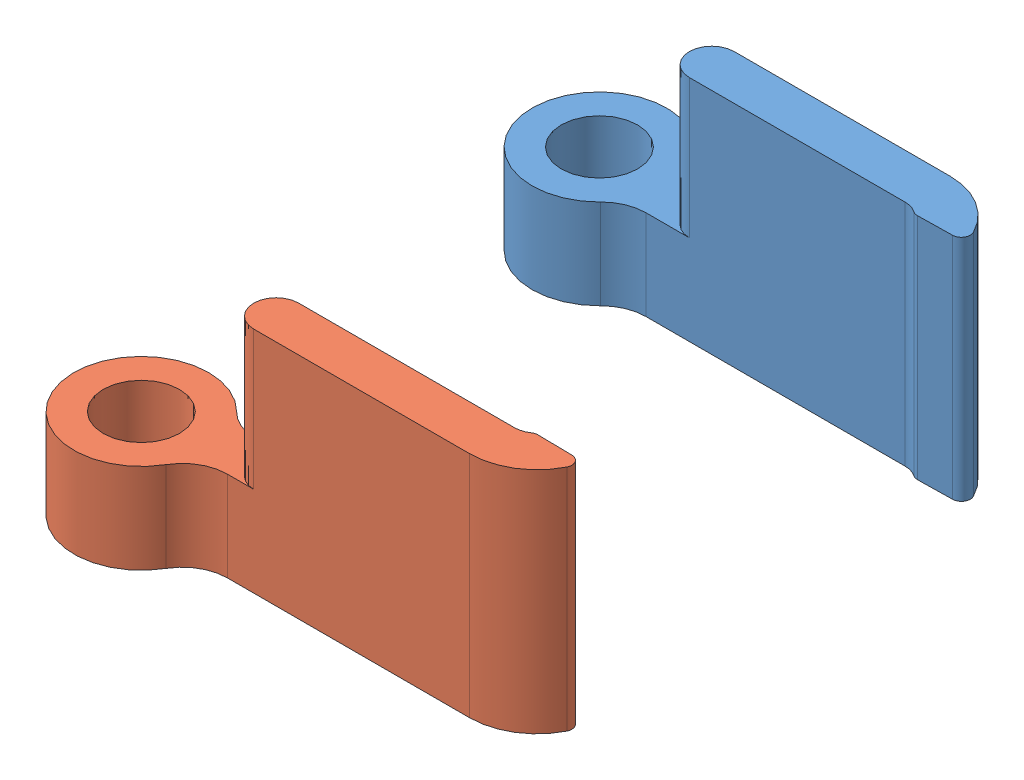
SolidWorks assembly Assem2, configuration Default. Lengths in mm.
Overall size (26.45 12.92 33.5).
2 component instances, 2 part files, 6 mates.
Components (placement in the parent):
- Spring Thing-1: Spring Thing [Default] at (-2.159 -3.8562 -1.905) size (26.45 12.92 7.62)
- Other Spring Thing-1: Other Spring Thing [Default] at (-2.159 -3.8562 23.9788) size (26.45 12.92 7.62)
Mates (geometry in assembly coordinates):
- Coincident1: coincident aligned: plane of Spring Thing-1 through (-2.159 0 -1.905) normal (0 -1 0); plane of Other Spring Thing-1 through (-2.159 0 23.9788) normal (0 -1 0)
- Coincident2: coincident aligned: plane of Spring Thing-1 through (17.0251 16.7738 0) normal (0 0 1); plane of assembly through (0 0 0) normal (0 0 1)
- Coincident3: coincident anti-aligned: plane of Spring Thing-1 through (-2.159 0 -1.905) normal (0 -1 0); plane of assembly through (0 0 0) normal (0 1 0)
- Tangent1: tangent aligned: cylinder of Spring Thing-1 through (-2.159 16.7738 -1.905) axis (0 -1 0) radius 2.159; plane of assembly through (0 0 0) normal (1 0 0)
- Parallel1: parallel anti-aligned: plane of Spring Thing-1 through (17.0251 16.7738 0) normal (0 0 1); plane of Other Spring Thing-1 through (17.0251 16.7738 22.0738) normal (0 0 -1)
- Tangent2: tangent aligned: cylinder of Other Spring Thing-1 through (-2.159 16.7738 23.9788) axis (0 -1 0) radius 2.159; plane of assembly through (0 0 0) normal (1 0 0)
